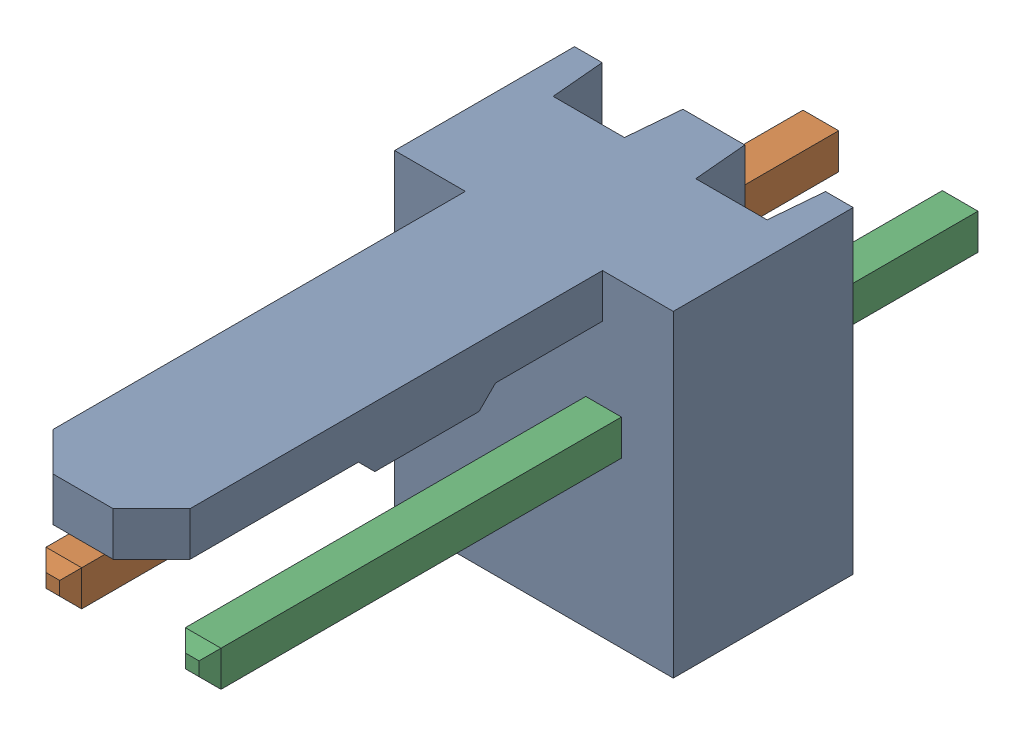
SolidWorks assembly Molex PCB 2 pin v2_3, configuration Predeterminado. Lengths in mm.
Overall size (5.08 5.79 14.92).
3 component instances, 2 part files, 0 mates.
Components (placement in the parent):
- BASE9710016_1-1: BASE9710016_1 [Predeterminado] at (2.54 2.895 -8.22) size (5.08 5.79 11.5)
- PINO9710016_1-1: PINO9710016_1 [Predeterminado] at (1.27 3.325 -0.72) size (0.65 0.65 14.2)
- PINO9710016_1-2: PINO9710016_1 [Predeterminado] at (3.81 3.325 -0.72) size (0.65 0.65 14.2)
